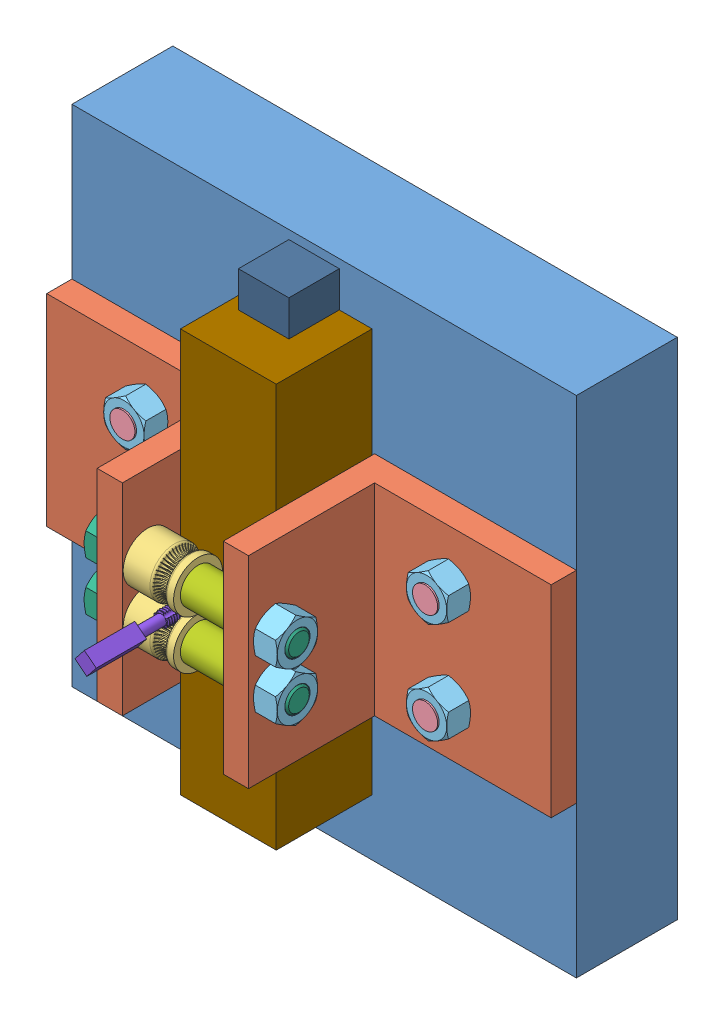
SolidWorks assembly Jig, configuration Default. Lengths in mm.
Overall size (100 100 64.29).
22 component instances, 10 part files, 36 mates.
Components (placement in the parent):
- base-1: base [Default] at (-12.8274 -1.3553 -2.3104) size (100 100 20)
- L-1: L [Default] at (-22.8274 -21.3553 17.6896) x (-1 0 0) z (0 1 0) size (40 30 40)
- L-2: L [Default] at (-2.8274 18.6447 17.6896) x (1 0 0) z (0 -1 0) size (40 30 40)
- trator-1: trator [Default] at (-8.8274 -6.2053 42.6896) x (0 0.031048 0.999518) z (-1 0 0) size (9.7 9.7 10)
- trator-2: trator [Default] at (-8.8274 3.4947 42.6896) x (0 0 1) z (-1 0 0) size (9.7 9.7 10)
- Flat Head Screw_AM-1: Flat Head Screw_AM [B18.6.7M - M5 x 0.8 x 30 Type I Cross Recessed FHMS --30N] at (17.1726 8.6447 -2.3104) x (0 0 1) z (-0.923728 -0.383049 0) size (30 9.3 9.3)
- Flat Head Screw_AM-2: Flat Head Screw_AM [B18.6.7M - M5 x 0.8 x 30 Type I Cross Recessed FHMS --30N] at (17.1726 -11.3553 -2.3104) x (0 0 1) z (-0.923728 -0.383049 0) size (30 9.3 9.3)
- Flat Head Screw_AM-3: Flat Head Screw_AM [B18.6.7M - M5 x 0.8 x 30 Type I Cross Recessed FHMS --30N] at (-42.8274 -11.3553 -2.3104) x (0 0 1) z (-0.923728 -0.383049 0) size (30 9.3 9.3)
- Flat Head Screw_AM-4: Flat Head Screw_AM [B18.6.7M - M5 x 0.8 x 30 Type I Cross Recessed FHMS --30N] at (-42.8274 8.6447 -2.3104) x (0 0 1) z (-0.923728 -0.383049 0) size (30 9.3 9.3)
- Hex Nut Style 1_AM-1: Hex Nut Style 1_AM [B18.2.4.1M - Hex nut, Style 1,  M5 x 0.8 --D-N] at (17.1726 -11.3553 27.3896) size (8 9.24 4.7)
- Hex Nut Style 1_AM-2: Hex Nut Style 1_AM [B18.2.4.1M - Hex nut, Style 1,  M5 x 0.8 --D-N] at (17.1726 8.6447 27.3896) size (8 9.24 4.7)
- Hex Nut Style 1_AM-3: Hex Nut Style 1_AM [B18.2.4.1M - Hex nut, Style 1,  M5 x 0.8 --D-N] at (-42.8274 8.6447 27.3896) size (8 9.24 4.7)
- Hex Nut Style 1_AM-4: Hex Nut Style 1_AM [B18.2.4.1M - Hex nut, Style 1,  M5 x 0.8 --D-N] at (-42.8274 -11.3553 27.3896) size (8 9.24 4.7)
- Hex Bolt_AM-1: Hex Bolt_AM [B18.2.3.5M - Hex bolt M5 x 0.8 x 35 --16N] at (-31.4074 -6.2053 42.6896) size (38.58 9.24 8)
- Hex Bolt_AM-2: Hex Bolt_AM [B18.2.3.5M - Hex bolt M5 x 0.8 x 35 --16N] at (-31.4074 3.4947 42.6896) size (38.58 9.24 8)
- Hex Nut Style 1_AM-5: Hex Nut Style 1_AM [B18.2.4.1M - Hex nut, Style 1,  M5 x 0.8 --D-N] at (6.8726 -6.2053 42.6896) x (0 0 -1) z (1 0 0) size (8 9.24 4.7)
- Hex Nut Style 1_AM-6: Hex Nut Style 1_AM [B18.2.4.1M - Hex nut, Style 1,  M5 x 0.8 --D-N] at (6.8726 3.4947 42.6896) x (0 0 -1) z (1 0 0) size (8 9.24 4.7)
- washer-1: washer [Default] at (-2.8274 3.4947 42.6896) x (0 0 1) z (-1 0 0) size (7 7 10)
- washer-2: washer [Default] at (-2.8274 -6.2053 42.6896) x (0 0 1) z (-1 0 0) size (7 7 10)
- tap-1: tap [Default] at (-15.8274 -1.7053 57.9828) x (0.783121 -0.621869 0) z (0 0 -1) size (3 3 34)
- bit20x20-1: bit20x20 [Default] at (-12.8274 39.8372 27.1896) x (1 0 0) z (0 -1 0) size (19 19 80) (hidden)
- bit10x10-1: bit10x10 [Default] at (-14.8274 46.9136 22.6896) x (1 0 0) z (0 -1 0) size (10 10 80)
Mates (geometry in assembly coordinates):
- Coincident5: coincident anti-aligned: circle of L-1; circle of trator-1
- Coincident6: coincident anti-aligned: circle of L-1; circle of trator-2
- Lock1: lock: unknown of base-1; unknown of L-1
- Lock2: lock: unknown of base-1; unknown of L-2
- Concentric1: concentric anti-aligned: cylinder of base-1 through (17.1726 8.6447 -2.3104) axis (0 0 -1) radius 2.65; cone of Flat Head Screw_AM-1 through (17.1726 8.6447 -1.7604) axis (0 0 1)
- Concentric2: concentric anti-aligned: cylinder of base-1 through (17.1726 -11.3553 -2.3104) axis (0 0 -1) radius 2.65; cone of Flat Head Screw_AM-2 through (17.1726 -11.3553 -1.7604) axis (0 0 1)
- Concentric3: concentric anti-aligned: cylinder of base-1 through (-42.8274 -11.3553 -2.3104) axis (0 0 -1) radius 2.65; cone of Flat Head Screw_AM-3 through (-42.8274 -11.3553 -1.7604) axis (0 0 1)
- Concentric4: concentric anti-aligned: cylinder of base-1 through (-42.8274 8.6447 -2.3104) axis (0 0 -1) radius 2.65; cone of Flat Head Screw_AM-4 through (-42.8274 8.6447 -1.7604) axis (0 0 1)
- Coincident8: coincident aligned: plane of base-1 through (37.1726 48.6447 -2.3104) normal (0 0 -1); plane of Flat Head Screw_AM-3 through (-42.8274 -11.3553 -2.3104) normal (0 0 -1)
- Coincident9: coincident aligned: plane of base-1 through (37.1726 48.6447 -2.3104) normal (0 0 -1); plane of Flat Head Screw_AM-2 through (17.1726 -11.3553 -2.3104) normal (0 0 -1)
- Coincident10: coincident aligned: plane of base-1 through (37.1726 48.6447 -2.3104) normal (0 0 -1); plane of Flat Head Screw_AM-1 through (17.1726 8.6447 -2.3104) normal (0 0 -1)
- Coincident11: coincident aligned: plane of base-1 through (37.1726 48.6447 -2.3104) normal (0 0 -1); plane of Flat Head Screw_AM-4 through (-42.8274 8.6447 -2.3104) normal (0 0 -1)
- Concentric5: concentric anti-aligned: cylinder of L-2 through (17.1726 -11.3553 57.6896) axis (0 0 -1) radius 2.5; cylinder of Hex Nut Style 1_AM-1 through (17.1726 -11.3553 2.3521) axis (0 0 1) radius 2.5
- Coincident12: coincident anti-aligned: plane of L-2 through (2.1726 -21.3553 22.6896) normal (0 0 1); plane of Hex Nut Style 1_AM-1 through (9.1726 -11.3553 22.6896) normal (0 0 -1)
- Concentric6: concentric anti-aligned: cylinder of L-2 through (17.1726 8.6447 57.6896) axis (0 0 -1) radius 2.5; cylinder of Hex Nut Style 1_AM-2 through (17.1726 8.6447 2.3521) axis (0 0 1) radius 2.5
- Coincident13: coincident anti-aligned: plane of L-2 through (2.1726 -21.3553 22.6896) normal (0 0 1); plane of Hex Nut Style 1_AM-2 through (9.1726 8.6447 22.6896) normal (0 0 -1)
- Concentric7: concentric anti-aligned: cylinder of L-1 through (-42.8274 8.6447 57.6896) axis (0 0 -1) radius 2.5; cylinder of Hex Nut Style 1_AM-3 through (-42.8274 8.6447 2.3521) axis (0 0 1) radius 2.5
- Coincident14: coincident anti-aligned: plane of L-1 through (-27.8274 18.6447 22.6896) normal (0 0 1); plane of Hex Nut Style 1_AM-3 through (-50.8274 8.6447 22.6896) normal (0 0 -1)
- Concentric8: concentric anti-aligned: cylinder of L-1 through (-42.8274 -11.3553 57.6896) axis (0 0 -1) radius 2.5; cylinder of Hex Nut Style 1_AM-4 through (-42.8274 -11.3553 2.3521) axis (0 0 1) radius 2.5
- Coincident15: coincident anti-aligned: plane of L-1 through (-27.8274 18.6447 22.6896) normal (0 0 1); plane of Hex Nut Style 1_AM-4 through (-50.8274 -11.3553 22.6896) normal (0 0 -1)
- Concentric9: concentric anti-aligned: cylinder of L-1 through (-62.8274 -6.2053 42.6896) axis (1 0 0) radius 2.5; cylinder of Hex Bolt_AM-1 through (-31.4074 -6.2053 42.6896) axis (-1 0 0) radius 2.5
- Coincident16: coincident anti-aligned: plane of L-1 through (-27.8274 18.6447 22.6896) normal (-1 0 0); plane of Hex Bolt_AM-1 through (-27.8274 -1.5865 42.6896) normal (1 0 0)
- Concentric10: concentric anti-aligned: cylinder of L-1 through (-62.8274 3.4947 42.6896) axis (1 0 0) radius 2.5; cylinder of Hex Bolt_AM-2 through (-31.4074 3.4947 42.6896) axis (-1 0 0) radius 2.5
- Coincident17: coincident anti-aligned: plane of L-1 through (-27.8274 18.6447 22.6896) normal (-1 0 0); plane of Hex Bolt_AM-2 through (-27.8274 8.1135 42.6896) normal (1 0 0)
- Concentric11: concentric anti-aligned: cylinder of L-2 through (37.1726 -6.2053 42.6896) axis (-1 0 0) radius 2.5; cylinder of Hex Nut Style 1_AM-5 through (-18.1649 -6.2053 42.6896) axis (1 0 0) radius 2.5
- Coincident18: coincident anti-aligned: plane of L-2 through (2.1726 -21.3553 22.6896) normal (1 0 0); plane of Hex Nut Style 1_AM-5 through (2.1726 -6.2053 50.6896) normal (-1 0 0)
- Concentric12: concentric anti-aligned: cylinder of L-2 through (37.1726 3.4947 42.6896) axis (-1 0 0) radius 2.5; cylinder of Hex Nut Style 1_AM-6 through (-18.1649 3.4947 42.6896) axis (1 0 0) radius 2.5
- Coincident19: coincident anti-aligned: plane of L-2 through (2.1726 -21.3553 22.6896) normal (1 0 0); plane of Hex Nut Style 1_AM-6 through (2.1726 3.4947 50.6896) normal (-1 0 0)
- Coincident20: coincident aligned: circle of trator-1; circle of washer-2
- Coincident21: coincident aligned: circle of trator-2; circle of washer-1
- Parallel1: parallel aligned: plane of base-1 through (37.1726 48.6447 17.6896) normal (0 0 1); plane of tap-1 through (-16.0692 0.4021 61.9828) normal (0 0 1)
- Coincident23: coincident anti-aligned: plane of base-1 through (37.1726 48.6447 17.6896) normal (0 0 1); plane of bit20x20-1 through (-22.3274 -40.1628 17.6896) normal (0 0 -1)
- Width1: width: plane of bit20x20-1 through (-22.3274 -40.1628 17.6896) normal (-1 0 0); plane of bit20x20-1 through (-3.3274 -40.1628 17.6896) normal (1 0 0); plane of L-2 through (2.1726 -21.3553 22.6896) normal (1 0 0); plane of L-1 through (-27.8274 18.6447 22.6896) normal (-1 0 0)
- Concentric13: concentric anti-aligned: circle of base-1; cylinder of tap-1 through (-15.8274 -1.7053 51.9828) axis (0 0 -1) radius 1
- Coincident24: coincident anti-aligned: plane of base-1 through (37.1726 48.6447 17.6896) normal (0 0 1); plane of bit10x10-1 through (-19.8274 -33.0864 17.6896) normal (0 0 -1)
- Distance1: distance = 3 mm anti-aligned: plane of L-1 through (-22.8274 18.6447 17.6896) normal (1 0 0); plane of bit10x10-1 through (-19.8274 -33.0864 17.6896) normal (-1 0 0)
